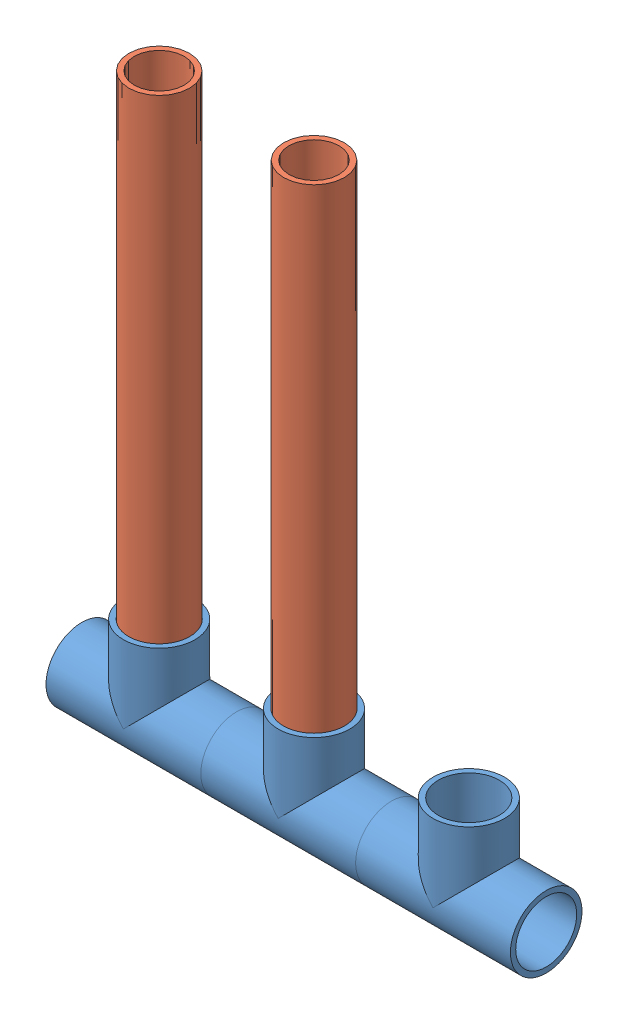
SolidWorks assembly Lowerbody, configuration Default. Lengths in mm.
Overall size (323.09 409.07 49.78).
5 component instances, 2 part files, 12 mates.
Components (placement in the parent):
- T.PVCcoupling-1: T.PVCcoupling [4880K44] at (-120.1207 85.304 147.4933) size (107.7 78.74 49.78)
- T.PVCcoupling-2: T.PVCcoupling [4880K44] at (-12.4247 85.304 147.4933) size (107.7 78.74 49.78)
- T.PVCcoupling-3: T.PVCcoupling [4880K44] at (-227.8167 85.304 147.4933) size (107.7 78.74 49.78)
- Torso.PVC-1: Torso.PVC [Default] at (-227.8167 107.529 147.4933) x (0 1 0) z (0 0 1) size (361.95 42.16 42.16)
- Torso.PVC-2: Torso.PVC [Default] at (-120.1207 107.529 147.4933) x (0 1 0) z (0 0 1) size (361.95 42.16 42.16)
Mates (geometry in assembly coordinates):
- Concentric1: concentric aligned: cylinder of T.PVCcoupling-1 through (-97.8957 85.304 147.4933) axis (-1 0 0) radius 24.892; cylinder of T.PVCcoupling-2 through (9.8003 85.304 147.4933) axis (-1 0 0) radius 24.892
- Concentric2: concentric aligned: cylinder of T.PVCcoupling-1 through (-97.8957 85.304 147.4933) axis (-1 0 0) radius 24.892; cylinder of T.PVCcoupling-3 through (-205.5917 85.304 147.4933) axis (-1 0 0) radius 24.892
- Coincident1: coincident aligned: plane of T.PVCcoupling-1 through (-120.1207 85.304 147.4933) normal (0 0 1); plane of T.PVCcoupling-2 through (-12.4247 85.304 147.4933) normal (0 0 1)
- Coincident2: coincident aligned: plane of T.PVCcoupling-1 through (-120.1207 85.304 147.4933) normal (0 0 1); plane of T.PVCcoupling-3 through (-227.8167 85.304 147.4933) normal (0 0 1)
- Coincident3: coincident anti-aligned: plane of T.PVCcoupling-1 through (-173.9687 60.412 147.4933) normal (-1 0 0); plane of T.PVCcoupling-3 through (-173.9687 60.412 147.4933) normal (1 0 0)
- Coincident4: coincident anti-aligned: plane of T.PVCcoupling-1 through (-66.2727 60.412 147.4933) normal (1 0 0); plane of T.PVCcoupling-2 through (-66.2727 60.412 147.4933) normal (-1 0 0)
- Concentric3: concentric aligned: cone of T.PVCcoupling-1 through (-120.1207 139.152 147.4933) axis (0 -1 0); cylinder of Torso.PVC-2 through (-120.1207 89.8679 147.4933) axis (0 -1 0) radius 21.082
- Concentric5: concentric aligned: cone of T.PVCcoupling-3 through (-227.8167 139.152 147.4933) axis (0 -1 0); cylinder of Torso.PVC-1 through (-227.8167 89.8679 147.4933) axis (0 -1 0) radius 21.082
- Coincident5: coincident anti-aligned: plane of T.PVCcoupling-1 through (-120.1207 107.529 147.4933) normal (0 1 0); plane of Torso.PVC-2 through (-141.2027 107.529 147.4933) normal (0 -1 0)
- Coincident6: coincident anti-aligned: plane of T.PVCcoupling-3 through (-227.8167 107.529 147.4933) normal (0 1 0); plane of Torso.PVC-1 through (-248.8987 107.529 147.4933) normal (0 -1 0)
- Coincident8: coincident aligned: plane of T.PVCcoupling-1 through (-120.1207 85.304 147.4933) normal (0 0 1); plane of Torso.PVC-1 through (-227.8167 107.529 147.4933) normal (0 0 1)
- Coincident9: coincident aligned: plane of T.PVCcoupling-1 through (-120.1207 85.304 147.4933) normal (0 0 1); plane of Torso.PVC-2 through (-120.1207 107.529 147.4933) normal (0 0 1)
